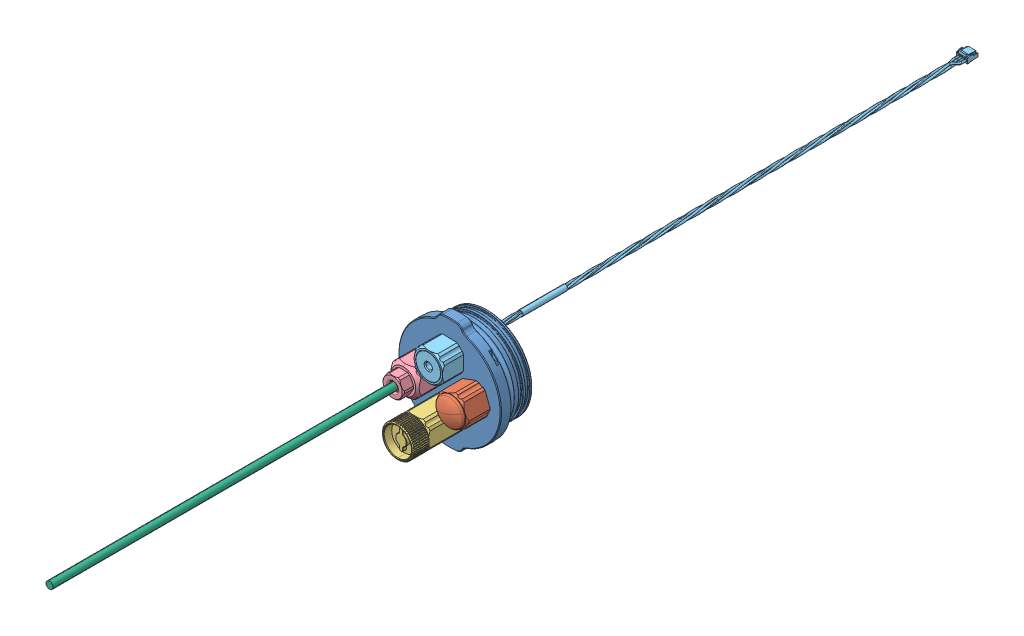
SolidWorks assembly cap-connectors, configuration Default. Lengths in mm.
Overall size (58 63.5 233.5).
9 component instances, 9 part files, 17 mates.
Components (placement in the parent):
- WTE2-M-LOCKING-FLANGE-CAP-4-HOLE-R1-1: WTE2-M-LOCKING-FLANGE-CAP-4-HOLE-R1 [Default] at (-25.5895 42.0149 57.9716) size (58 63.5 21.5)
- INDICATOR-M10-X-R2-PUBLIC-1: INDICATOR-M10-X-R2-PUBLIC [Default] at (-11.4474 42.0149 95.6518) x (-0.936712 -0.350102 0) z (-0.350102 0.936712 0) size (17.01 36.18 17.01)
- PRV-M10-ASM-R1-RP-1: PRV-M10-ASM-R1-RP [Default] at (-25.5895 27.8728 19.0909) x (-0.999972 -0.007535 0) z (-0.007535 0.999972 0) size (18 49.5 18)
- WLP-M10-4.5MM-PUBLIC-1: WLP-M10-4.5MM-PUBLIC [Default] at (-39.7317 42.0149 59.4716) x (-0.005349 -0.999986 0) z (-0.999986 0.005349 0) size (17.01 38 17.01)
- BAR02-ASM-R2-PUBLIC-1: BAR02-ASM-R2-PUBLIC [Default] at (-25.5895 56.1571 79.4716) x (-0.999645 0.026629 0) z (0.026629 0.999645 0) size (17.01 307.6 17.01)
- fathom-utp-4mm-mockup-1: fathom-utp-4mm-mockup [Default] at (-39.7317 42.0149 91.4716) x (0.199087 -0.979982 0) z (-0.979982 -0.199087 0) size (4 200 4)
- flange-led-ring-1: flange-led-ring [Default] at (-25.5895 42.0149 63.9716) x (1 0 0) z (0 1 0) size (45 1.6 45) (hidden)
- interior-lighting-1: interior-lighting [Default] at (-25.6645 42.1157 63.9516) x (-0.005386 -0.999985 0) z (0 0 -1) size (44.99 44.99 3.48)
- led-diffuser-1: led-diffuser [Default] at (-25.6645 42.1157 60.3702) x (-0.999985 0.005386 0) z (0.005386 0.999985 0) size (45.5 1 45.5)
Mates (geometry in assembly coordinates):
- Concentric1: concentric aligned: cylinder of WTE2-M-LOCKING-FLANGE-CAP-4-HOLE-R1-1 through (-39.7317 42.0149 79.4716) axis (0 0 1) radius 5.1; cylinder of WLP-M10-4.5MM-PUBLIC-1 through (-39.7317 42.0149 77.2553) axis (0 0 1) radius 4.1
- Concentric3: concentric aligned: cylinder of WTE2-M-LOCKING-FLANGE-CAP-4-HOLE-R1-1 through (-25.5895 56.1571 79.4716) axis (0 0 1) radius 5.1; cylinder of BAR02-ASM-R2-PUBLIC-1 through (-25.5895 56.1571 77.2553) axis (0 0 1) radius 4.1
- Concentric4: concentric aligned: cylinder of WTE2-M-LOCKING-FLANGE-CAP-4-HOLE-R1-1 through (-25.5895 27.8728 79.4716) axis (0 0 1) radius 5.1; cylinder of PRV-M10-ASM-R1-RP-1 through (-25.5895 27.8728 77.2553) axis (0 0 1) radius 4.1
- Concentric5: concentric aligned: cylinder of WTE2-M-LOCKING-FLANGE-CAP-4-HOLE-R1-1 through (-11.4474 42.0149 79.4716) axis (0 0 1) radius 5.1; cylinder of INDICATOR-M10-X-R2-PUBLIC-1 through (-11.4474 42.0149 77.2553) axis (0 0 1) radius 4.1
- Coincident2: coincident anti-aligned: plane of WTE2-M-LOCKING-FLANGE-CAP-4-HOLE-R1-1 through (-25.5895 42.0149 79.4716) normal (0 0 1); plane of BAR02-ASM-R2-PUBLIC-1 through (-17.9422 55.9534 79.4716) normal (0 0 -1)
- Coincident3: coincident anti-aligned: plane of WTE2-M-LOCKING-FLANGE-CAP-4-HOLE-R1-1 through (-25.5895 42.0149 79.4716) normal (0 0 1); plane of INDICATOR-M10-X-R2-PUBLIC-1 through (-4.2815 44.6932 79.4716) normal (0 0 -1)
- Coincident4: coincident anti-aligned: plane of WTE2-M-LOCKING-FLANGE-CAP-4-HOLE-R1-1 through (-25.5895 42.0149 79.4716) normal (0 0 1); plane of PRV-M10-ASM-R1-RP-1 through (-25.5319 20.223 79.4716) normal (0 0 -1)
- Coincident5: coincident anti-aligned: plane of WTE2-M-LOCKING-FLANGE-CAP-4-HOLE-R1-1 through (-25.5895 42.0149 79.4716) normal (0 0 1); plane of WLP-M10-4.5MM-PUBLIC-1 through (-39.6907 49.6748 79.4716) normal (0 0 -1)
- Concentric6: concentric anti-aligned: cylinder of WLP-M10-4.5MM-PUBLIC-1 through (-39.7317 42.0149 96.6759) axis (0 0 1) radius 2.45; cylinder of fathom-utp-4mm-mockup-1 through (-39.7317 42.0149 291.4716) axis (0 0 -1) radius 2
- Coincident6: coincident anti-aligned: plane of WLP-M10-4.5MM-PUBLIC-1 through (-39.6942 49.0148 91.4716) normal (0 0 1); plane of fathom-utp-4mm-mockup-1 through (-39.7317 42.0149 91.4716) normal (0 0 -1)
- Parallel1: parallel aligned: plane of WTE2-M-LOCKING-FLANGE-CAP-4-HOLE-R1-1 through (-25.5895 42.0149 57.9716) normal (0 0 -1); plane of flange-led-ring-1 through (-16.8942 37.3895 62.3716) normal (0 0 -1)
- Concentric7: concentric anti-aligned: cylinder of WTE2-M-LOCKING-FLANGE-CAP-4-HOLE-R1-1 through (-25.5895 42.0149 105.0528) axis (0 0 -1) radius 23; cylinder of flange-led-ring-1 through (-25.5895 42.0149 62.3716) axis (0 0 1) radius 22.5
- Concentric8: concentric anti-aligned: cylinder of WTE2-M-LOCKING-FLANGE-CAP-4-HOLE-R1-1 through (-16.3387 59.4056 105.0528) axis (0 0 -1) radius 3.302; cylinder of flange-led-ring-1 through (-16.3387 59.4056 62.3716) axis (0 0 1) radius 2.802
- Distance1: distance = 6 mm anti-aligned: plane of WTE2-M-LOCKING-FLANGE-CAP-4-HOLE-R1-1 through (-25.5895 42.0149 57.9716) normal (0 0 -1); plane of flange-led-ring-1 through (-16.8942 37.3895 63.9716) normal (0 0 1)
- Coincident8: coincident aligned: plane of flange-led-ring-1 through (-16.8942 37.3895 62.3716) normal (0 0 -1); plane of interior-lighting-1 through (-25.6745 42.1158 62.3716) normal (0 0 -1)
- Symmetric1: symmetric aligned: plane of interior-lighting-1 through (-5.6702 41.008 62.0216) normal (-0.999833 0.005386 -0.017452); plane of led-diffuser-1 through (-45.6588 43.2235 62.0216) normal (0.999833 -0.005386 -0.017452); plane of interior-lighting-1 through (-25.6645 42.1157 60.3702) normal (-0.999985 0.005386 0)
- Symmetric2: symmetric aligned: plane of interior-lighting-1 through (-26.7722 22.1214 62.0216) normal (0.005386 0.999833 -0.017452); plane of led-diffuser-1 through (-24.5568 62.1101 62.0216) normal (-0.005386 -0.999833 -0.017452); plane of interior-lighting-1 through (-25.6645 42.1157 60.3702) normal (0.005386 0.999985 0)
